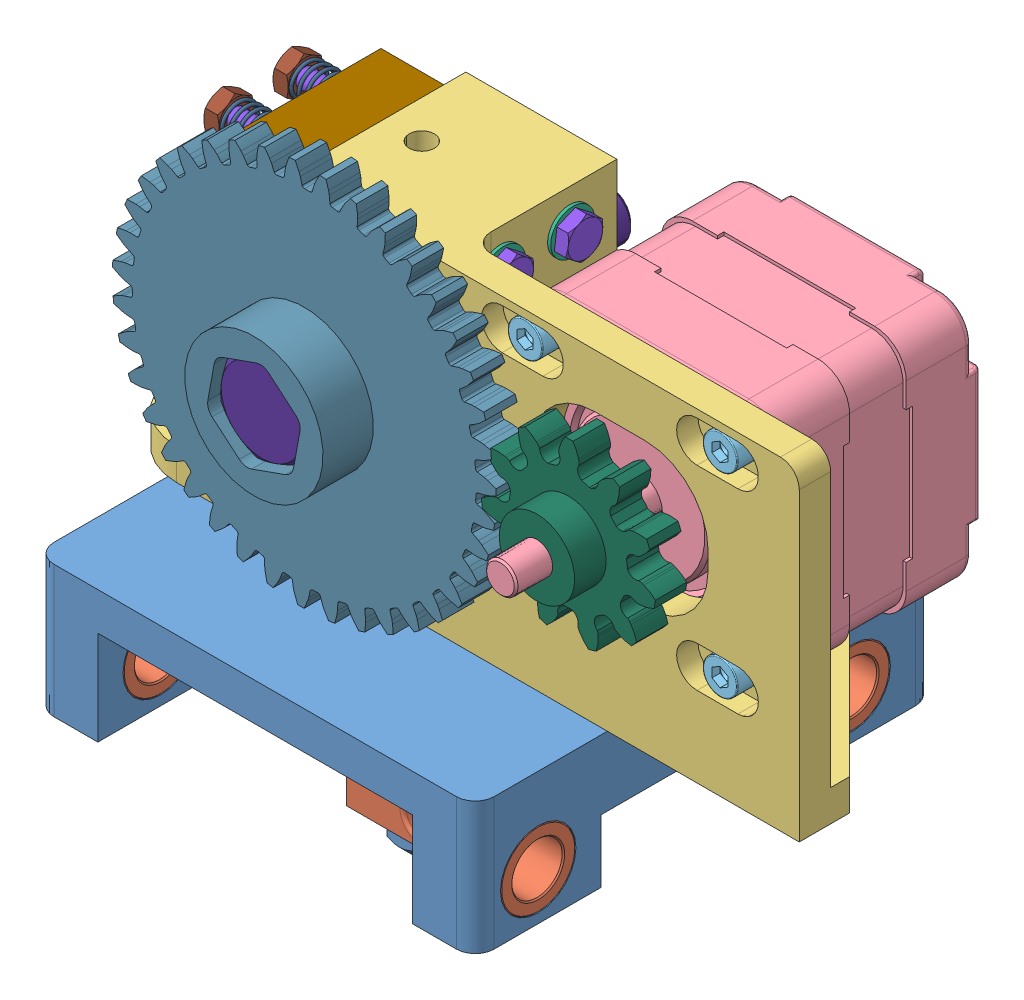
SolidWorks assembly X-Chariot, configuration Défaut. Lengths in mm.
Overall size (113.48 121.48 91.5).
86 component instances, 22 part files, 11 mates.
Components (placement in the parent):
- Chariot_Extrudeuse-1: Chariot_Extrudeuse [Défaut] at (18.2615 62.9748 98.4963) x (1 0 0) z (0 0 -1) size (70 21 91.5)
- BG 12x8x10-4: BG 12x8x10 [Défaut] at (78.2615 49.4748 88.4963) x (0 0.932939 0.360033) z (1 0 0) size (12 12 10)
- X-Tete_Extrusion-2: X-Tete_Extrusion [Défaut] at (67.2193 48.3843 48.66) size (113.48 192.54 59.4)
  - Extruder Body-1: Extruder Body [Défaut] at (51.5422 19.5906 0.8363) x (-1 0 0) z (0 0 -1) size (109 51.5 28)
  - plain washer grade a_din_Washer DIN 125 - A 3.7-1: plain washer grade a_din_Washer DIN 125 - A 3.7 [Défaut] at (-44.9578 19.5906 7.8363) x (0 -1 0) z (0 0 1) size (0.5 8 8) (hidden)
  - plain washer grade a_din_Washer DIN 125 - A 3.7-2: plain washer grade a_din_Washer DIN 125 - A 3.7 [Défaut] at (-44.9578 19.5906 21.8363) x (0 -1 0) z (0 0 1) size (0.5 8 8) (hidden)
  - plain washer grade a_din_Washer DIN 125 - A 3.7-3: plain washer grade a_din_Washer DIN 125 - A 3.7 [Défaut] at (16.0422 19.5906 6.5863) x (0 -1 0) z (0 0 1) size (0.5 8 8) (hidden)
  - plain washer grade a_din_Washer DIN 125 - A 3.7-4: plain washer grade a_din_Washer DIN 125 - A 3.7 [Défaut] at (16.0422 19.5906 18.0863) x (0 -1 0) z (0 0 1) size (0.5 8 8) (hidden)
  - plain washer grade a_din_Washer DIN 125 - A 3.7-5: plain washer grade a_din_Washer DIN 125 - A 3.7 [Défaut] at (16.0422 3.5906 6.5863) x (0 1 0) z (0 0 1) size (0.5 8 8) (hidden)
  - plain washer grade a_din_Washer DIN 125 - A 3.7-6: plain washer grade a_din_Washer DIN 125 - A 3.7 [Défaut] at (16.0422 3.5906 18.0863) x (0 1 0) z (0 0 1) size (0.5 8 8) (hidden)
  - plain washer grade a_din_Washer DIN 125 - A 3.7-7: plain washer grade a_din_Washer DIN 125 - A 3.7 [Défaut] at (-44.9578 3.5906 7.8363) x (0 1 0) z (0 0 1) size (0.5 8 8) (hidden)
  - plain washer grade a_din_Washer DIN 125 - A 3.7-8: plain washer grade a_din_Washer DIN 125 - A 3.7 [Défaut] at (-44.9578 3.5906 21.8363) x (0 1 0) z (0 0 1) size (0.5 8 8) (hidden)
  - hex bolt gradeb_iso_ISO 4015 - M3 x 20 x 20-C-1: hex bolt gradeb_iso_ISO 4015 - M3 x 20 x 20-C [Défaut] at (-44.9578 22.0906 21.8363) x (0 -1 0) z (0 0 1) size (22 6.35 5.5) (hidden)
  - hex bolt gradeb_iso_ISO 4015 - M3 x 20 x 20-C-2: hex bolt gradeb_iso_ISO 4015 - M3 x 20 x 20-C [Défaut] at (-44.9578 22.0906 7.8363) x (0 -1 0) z (0 0 1) size (22 6.35 5.5) (hidden)
  - hex bolt gradeb_iso_ISO 4015 - M3 x 20 x 20-C-3: hex bolt gradeb_iso_ISO 4015 - M3 x 20 x 20-C [Défaut] at (16.0422 22.0906 6.5863) x (0 -1 0) z (0 0 1) size (22 6.35 5.5) (hidden)
  - hex bolt gradeb_iso_ISO 4015 - M3 x 20 x 20-C-4: hex bolt gradeb_iso_ISO 4015 - M3 x 20 x 20-C [Défaut] at (16.0422 22.0906 18.0863) x (0 -1 0) z (0 0 1) size (22 6.35 5.5) (hidden)
  - hex nut style 1 gradeab_iso_Hexagon Nut ISO - 4032 - M3 - D - C-1: hex nut style 1 gradeab_iso_Hexagon Nut ISO - 4032 - M3 - D - C [Défaut] at (-44.9578 0.6906 21.8363) x (1 0 0) z (0 -1 0) size (5.5 6.35 2.4) (hidden)
  - hex nut style 1 gradeab_iso_Hexagon Nut ISO - 4032 - M3 - D - C-2: hex nut style 1 gradeab_iso_Hexagon Nut ISO - 4032 - M3 - D - C [Défaut] at (-44.9578 0.6906 7.8363) x (1 0 0) z (0 -1 0) size (5.5 6.35 2.4) (hidden)
  - hex nut style 1 gradeab_iso_Hexagon Nut ISO - 4032 - M3 - D - C-3: hex nut style 1 gradeab_iso_Hexagon Nut ISO - 4032 - M3 - D - C [Défaut] at (16.0422 0.6906 6.5863) x (1 0 0) z (0 -1 0) size (5.5 6.35 2.4) (hidden)
  - hex nut style 1 gradeab_iso_Hexagon Nut ISO - 4032 - M3 - D - C-4: hex nut style 1 gradeab_iso_Hexagon Nut ISO - 4032 - M3 - D - C [Défaut] at (16.0422 0.6906 18.0863) x (1 0 0) z (0 -1 0) size (5.5 6.35 2.4) (hidden)
  - NEMA 17 Bipolar Stepper Motor-1: NEMA 17 Bipolar Stepper Motor [Défaut] at (23.0422 46.0906 7.3363) x (0 0 1) z (-1 0 0) size (57.01 39.01 39.01)
  - socket head cap screw_iso_ISO 4762 M3 x 5 --- 5C-1: socket head cap screw_iso_ISO 4762 M3 x 5 --- 5C [Défaut] at (7.5422 61.5906 28.4363) x (0 0 -1) z (1 0 0) size (8 5.5 5.5)
  - socket head cap screw_iso_ISO 4762 M3 x 5 --- 5C-2: socket head cap screw_iso_ISO 4762 M3 x 5 --- 5C [Défaut] at (38.5422 61.5906 28.4363) x (0 0 -1) z (1 0 0) size (8 5.5 5.5)
  - socket head cap screw_iso_ISO 4762 M3 x 5 --- 5C-3: socket head cap screw_iso_ISO 4762 M3 x 5 --- 5C [Défaut] at (7.5422 30.5906 28.4363) x (0 0 -1) z (1 0 0) size (8 5.5 5.5)
  - socket head cap screw_iso_ISO 4762 M3 x 5 --- 5C-4: socket head cap screw_iso_ISO 4762 M3 x 5 --- 5C [Défaut] at (38.5422 30.5906 28.4363) x (0 0 -1) z (1 0 0) size (8 5.5 5.5)
  - plain washer grade a_din_Washer DIN 125 - A 3.2-1: plain washer grade a_din_Washer DIN 125 - A 3.2 [Défaut] at (-29.4578 60.0906 8.3363) size (0.5 7 7)
  - plain washer grade a_din_Washer DIN 125 - A 3.2-2: plain washer grade a_din_Washer DIN 125 - A 3.2 [Défaut] at (-29.9578 60.0906 8.3363) size (0.5 7 7)
  - plain washer grade a_din_Washer DIN 125 - A 3.2-3: plain washer grade a_din_Washer DIN 125 - A 3.2 [Défaut] at (-30.4578 60.0906 8.3363) size (0.5 7 7)
  - plain washer grade a_din_Washer DIN 125 - A 3.2-4: plain washer grade a_din_Washer DIN 125 - A 3.2 [Défaut] at (-30.9578 60.0906 8.3363) x (1 0 0) z (0 0.451194 0.892426) size (0.5 7 7)
  - Smooth Rod - f8x23-1: Smooth Rod - f8x23 [Défaut] at (-34.4578 46.0906 2.3363) x (1 0 0) z (0 -1 0) size (8 23 8)
  - plain washer grade a_din_Washer DIN 125 - A 3.2-5: plain washer grade a_din_Washer DIN 125 - A 3.2 [Défaut] at (-5.4578 60.0906 19.3363) x (-1 0 0) z (0 0.924225 0.381849) size (0.5 7 7)
  - plain washer grade a_din_Washer DIN 125 - A 3.2-6: plain washer grade a_din_Washer DIN 125 - A 3.2 [Défaut] at (-5.4578 60.0906 8.3363) x (-1 0 0) z (0 0.924225 0.381849) size (0.5 7 7)
  - plain washer grade a_din_Washer DIN 125 - A 3.2-7: plain washer grade a_din_Washer DIN 125 - A 3.2 [Défaut] at (-5.4578 32.0906 8.3363) x (-1 0 0) z (0 0.924225 0.381849) size (0.5 7 7)
  - plain washer grade a_din_Washer DIN 125 - A 3.2-8: plain washer grade a_din_Washer DIN 125 - A 3.2 [Défaut] at (-5.4578 32.0906 19.3363) x (-1 0 0) z (0 0.924225 0.381849) size (0.5 7 7)
  - plain washer grade a_din_Washer DIN 125 - A 3.2-9: plain washer grade a_din_Washer DIN 125 - A 3.2 [Défaut] at (-29.4578 60.0906 19.3363) size (0.5 7 7)
  - plain washer grade a_din_Washer DIN 125 - A 3.2-10: plain washer grade a_din_Washer DIN 125 - A 3.2 [Défaut] at (-29.4578 32.0906 19.3363) size (0.5 7 7)
  - plain washer grade a_din_Washer DIN 125 - A 3.2-11: plain washer grade a_din_Washer DIN 125 - A 3.2 [Défaut] at (-29.4578 32.0906 8.3363) size (0.5 7 7)
  - plain washer grade a_din_Washer DIN 125 - A 3.2-12: plain washer grade a_din_Washer DIN 125 - A 3.2 [Défaut] at (-29.9578 60.0906 19.3363) size (0.5 7 7)
  - plain washer grade a_din_Washer DIN 125 - A 3.2-13: plain washer grade a_din_Washer DIN 125 - A 3.2 [Défaut] at (-30.4578 60.0906 19.3363) size (0.5 7 7)
  - plain washer grade a_din_Washer DIN 125 - A 3.2-14: plain washer grade a_din_Washer DIN 125 - A 3.2 [Défaut] at (-29.9578 32.0906 19.3363) size (0.5 7 7)
  - plain washer grade a_din_Washer DIN 125 - A 3.2-15: plain washer grade a_din_Washer DIN 125 - A 3.2 [Défaut] at (-30.4578 32.0906 19.3363) size (0.5 7 7)
  - plain washer grade a_din_Washer DIN 125 - A 3.2-16: plain washer grade a_din_Washer DIN 125 - A 3.2 [Défaut] at (-30.9578 32.0906 19.3363) size (0.5 7 7)
  - plain washer grade a_din_Washer DIN 125 - A 3.2-17: plain washer grade a_din_Washer DIN 125 - A 3.2 [Défaut] at (-29.9578 32.0906 8.3363) size (0.5 7 7)
  - plain washer grade a_din_Washer DIN 125 - A 3.2-18: plain washer grade a_din_Washer DIN 125 - A 3.2 [Défaut] at (-30.4578 32.0906 8.3363) size (0.5 7 7)
  - plain washer grade a_din_Washer DIN 125 - A 3.2-19: plain washer grade a_din_Washer DIN 125 - A 3.2 [Défaut] at (-30.9578 32.0906 8.3363) size (0.5 7 7)
  - M3x45_ISO 4015 - M3 x 45 x 12-C-1: M3x45_ISO 4015 - M3 x 45 x 12-C [Défaut] at (-2.9578 60.0906 19.3363) x (-1 0 0) z (0 -0.924225 -0.381849) size (47 6.35 5.5)
  - M3x45_ISO 4015 - M3 x 45 x 12-C-2: M3x45_ISO 4015 - M3 x 45 x 12-C [Défaut] at (-2.9578 32.0906 8.3363) x (-1 0 0) z (0 -0.924225 -0.381849) size (47 6.35 5.5)
  - M3x45_ISO 4015 - M3 x 45 x 12-C-3: M3x45_ISO 4015 - M3 x 45 x 12-C [Défaut] at (-2.9578 32.0906 19.3363) x (-1 0 0) z (0 -0.924225 -0.381849) size (47 6.35 5.5)
  - M3x45_ISO 4015 - M3 x 45 x 12-C-4: M3x45_ISO 4015 - M3 x 45 x 12-C [Défaut] at (-2.9578 60.0906 8.3363) x (-1 0 0) z (0 -0.924225 -0.381849) size (47 6.35 5.5)
  - Idler Body-1: Idler Body [Défaut] at (-41.4578 28.0906 25.3363) x (0 0 -1) z (1 0 0) size (23 36 10)
  - plain washer grade a_din_Washer DIN 125 - A 3.2-20: plain washer grade a_din_Washer DIN 125 - A 3.2 [Défaut] at (-30.9578 60.0906 19.3363) size (0.5 7 7)
  - plain washer grade a_din_Washer DIN 125 - A 3.2-21: plain washer grade a_din_Washer DIN 125 - A 3.2 [Défaut] at (-41.4578 60.0906 8.3363) x (1 0 0) z (0 -0.022823 0.99974) size (0.5 7 7)
  - plain washer grade a_din_Washer DIN 125 - A 3.2-22: plain washer grade a_din_Washer DIN 125 - A 3.2 [Défaut] at (-41.4578 60.0906 19.3363) size (0.5 7 7)
  - plain washer grade a_din_Washer DIN 125 - A 3.2-23: plain washer grade a_din_Washer DIN 125 - A 3.2 [Défaut] at (-41.4578 32.0906 19.3363) size (0.5 7 7)
  - plain washer grade a_din_Washer DIN 125 - A 3.2-24: plain washer grade a_din_Washer DIN 125 - A 3.2 [Défaut] at (-41.4578 32.0906 8.3363) size (0.5 7 7)
  - Ballpoint Pen Spring - Extruder-1: Ballpoint Pen Spring - Extruder [Défaut] at (-42.2078 60.0906 8.3363) x (0 0.991476 -0.130286) z (0 0.130286 0.991476) size (5.53 5.52 5.5)
  - Ballpoint Pen Spring - Extruder-2: Ballpoint Pen Spring - Extruder [Défaut] at (-42.2078 60.0906 19.3363) x (0 0.999694 0.024727) z (0 -0.024727 0.999694) size (5.53 5.52 5.5)
  - Ballpoint Pen Spring - Extruder-3: Ballpoint Pen Spring - Extruder [Défaut] at (-42.2078 32.0906 8.3363) x (0 0.999047 -0.043643) z (0 0.043643 0.999047) size (5.53 5.52 5.5)
  - Ballpoint Pen Spring - Extruder-4: Ballpoint Pen Spring - Extruder [Défaut] at (-42.2078 32.0906 19.3363) x (0 0.978843 -0.20461) z (0 0.20461 0.978843) size (5.53 5.52 5.5)
  - hex nut style 1 gradeab_iso_Hexagon Nut ISO - 4032 - M3 - D - C-5: hex nut style 1 gradeab_iso_Hexagon Nut ISO - 4032 - M3 - D - C [Défaut] at (-47.4578 60.0906 8.3363) x (0 0 -1) z (1 0 0) size (5.5 6.35 2.4)
  - hex nut style 1 gradeab_iso_Hexagon Nut ISO - 4032 - M3 - D - C-6: hex nut style 1 gradeab_iso_Hexagon Nut ISO - 4032 - M3 - D - C [Défaut] at (-47.4578 60.0906 19.3363) x (0 0 -1) z (1 0 0) size (5.5 6.35 2.4)
  - hex nut style 1 gradeab_iso_Hexagon Nut ISO - 4032 - M3 - D - C-7: hex nut style 1 gradeab_iso_Hexagon Nut ISO - 4032 - M3 - D - C [Défaut] at (-46.9578 32.0906 8.3363) x (0 0.019138 -0.999817) z (1 0 0) size (5.5 6.35 2.4)
  - hex nut style 1 gradeab_iso_Hexagon Nut ISO - 4032 - M3 - D - C-8: hex nut style 1 gradeab_iso_Hexagon Nut ISO - 4032 - M3 - D - C [Défaut] at (-47.4578 32.0906 19.3363) x (0 0.048448 -0.998826) z (1 0 0) size (5.5 6.35 2.4)
  - Fourreau-1: Fourreau [Défaut] at (-23.4578 24.5906 13.8363) x (-1 0 0) z (0 0 -1) size (20 44 20)
  - plain washer grade a_din_Washer DIN 125 - A 8.4-1: plain washer grade a_din_Washer DIN 125 - A 8.4 [Défaut] at (-18.9578 46.0906 28.8363) x (0 0 -1) z (0.999888 -0.014961 0) size (1.6 16 16)
  - Large Gear-1: Large Gear [Défaut] at (-47.7391 12.1511 32.0363) x (-0.64677 -0.762685 0) z (0 0 1) size (60.98 60.94 13)
  - plain washer grade a_din_Washer DIN 125 - A 8.4-2: plain washer grade a_din_Washer DIN 125 - A 8.4 [Défaut] at (-18.9578 46.0906 -0.7637) x (0 0 -1) z (0.808623 0.588327 0) size (1.6 16 16)
  - Motor Shaft Pulley - Extruder-1: Motor Shaft Pulley - Extruder [Défaut] at (5.4114 54.4147 32.0363) x (0.336489 -0.941687 0) z (0 0 1) size (27.58 27.61 10)
  - plain washer grade a_din_Washer DIN 125 - A 3.2-25: plain washer grade a_din_Washer DIN 125 - A 3.2 [Défaut] at (-29.4578 19.5906 28.8363) x (0 0 -1) z (1 0 0) size (0.5 7 7)
  - plain washer grade a_din_Washer DIN 125 - A 3.2-26: plain washer grade a_din_Washer DIN 125 - A 3.2 [Défaut] at (-17.4578 19.5906 28.8363) x (0 0 -1) z (1 0 0) size (0.5 7 7)
  - plain washer grade a_din_Washer DIN 125 - A 3.2-27: plain washer grade a_din_Washer DIN 125 - A 3.2 [Défaut] at (-29.4578 19.5906 0.8363) x (0 0 1) z (-1 0 0) size (0.5 7 7)
  - plain washer grade a_din_Washer DIN 125 - A 3.2-28: plain washer grade a_din_Washer DIN 125 - A 3.2 [Défaut] at (-17.4578 19.5906 0.8363) x (0 0 1) z (-1 0 0) size (0.5 7 7)
  - hex bolt gradeb_iso_ISO 4015 - M3 x 20 x 12-C-1: hex bolt gradeb_iso_ISO 4015 - M3 x 20 x 12-C [Défaut] at (-17.4578 19.5906 31.3363) x (0 0 -1) z (1 0 0) size (22 6.35 5.5)
  - hex bolt gradeb_iso_ISO 4015 - M3 x 20 x 12-C-2: hex bolt gradeb_iso_ISO 4015 - M3 x 20 x 12-C [Défaut] at (-29.4578 19.5906 31.3363) x (0 0 -1) z (1 0 0) size (22 6.35 5.5)
  - hex bolt gradeb_iso_ISO 4015 - M3 x 20 x 12-C-3: hex bolt gradeb_iso_ISO 4015 - M3 x 20 x 12-C [Défaut] at (-17.4578 19.5906 -1.6637) x (0 0 1) z (-1 0 0) size (22 6.35 5.5)
  - hex bolt gradeb_iso_ISO 4015 - M3 x 20 x 12-C-4: hex bolt gradeb_iso_ISO 4015 - M3 x 20 x 12-C [Défaut] at (-29.4578 19.5906 -1.6637) x (0 0 1) z (-1 0 0) size (22 6.35 5.5)
  - plain washer grade a_din_Washer DIN 125 - A 8.4-3: plain washer grade a_din_Washer DIN 125 - A 8.4 [Défaut] at (-18.9578 46.0906 30.4363) x (0 0 -1) z (0.820893 -0.571083 0) size (1.6 16 16)
  - hex bolt gradeb_iso_ISO 4015 - M8 x 50 x 22-C-1: hex bolt gradeb_iso_ISO 4015 - M8 x 50 x 22-C [Défaut] at (-18.9578 46.0906 43.7363) x (0 0 -1) z (0.98389 -0.178776 0) size (55.3 15.01 13)
  - radial ball bearing_68_skf_SKF - 608 - Full,DE,AC,Full_68-1: radial ball bearing_68_skf_SKF - 608 - Full,DE,AC,Full_68 [Défaut] at (-18.9578 46.0906 25.3363) x (0 0 1) z (-1 0 0) size (7.01 22 22)
  - radial ball bearing_68_skf_SKF - 608 - Full,DE,AC,Full_68-2: radial ball bearing_68_skf_SKF - 608 - Full,DE,AC,Full_68 [Défaut] at (-18.9578 46.0906 4.3363) x (0 0 1) z (-1 0 0) size (7.01 22 22)
  - radial ball bearing_68_skf_SKF - 608 - Full,DE,AC,Full_68-3: radial ball bearing_68_skf_SKF - 608 - Full,DE,AC,Full_68 [Défaut] at (-34.4578 46.0906 13.8363) x (0 0 -1) z (1 0 0) size (7.01 22 22)
  - Buse-1: Buse [Défaut] at (-23.4578 -32.4094 13.8363) x (0 1 0) z (0 0 1) size (13 8.89 7)
  - Support résistance-1: Support résistance [Défaut] at (-27.4578 -23.4094 5.8363) size (16 8 16)
- BG 12x8x10-8: BG 12x8x10 [Défaut] at (78.2615 49.4748 38.4963) x (0 0.071343 -0.997452) z (1 0 0) size (12 12 10)
- BG 12x8x10-10: BG 12x8x10 [Défaut] at (18.2615 49.4748 88.4963) x (0 0.19777 -0.980248) z (1 0 0) size (12 12 10)
- BG 12x8x10-12: BG 12x8x10 [Défaut] at (18.2615 49.4748 38.4963) x (0 0.28828 -0.957546) z (1 0 0) size (12 12 10)
Mates (geometry in assembly coordinates):
- Coaxiale5: concentric aligned: cylinder of Chariot_Extrudeuse-1 through (88.2615 49.4748 88.4963) axis (-1 0 0) radius 6; cylinder of BG 12x8x10-4 through (88.2615 49.4748 88.4963) axis (-1 0 0) radius 6
- Coïncidente3: coincident aligned: plane of Chariot_Extrudeuse-1 through (88.2615 56.9748 98.4963) normal (1 0 0); plane of BG 12x8x10-4 through (88.2615 49.4748 88.4963) normal (1 0 0)
- Coïncidente4: coincident anti-aligned: plane of Chariot_Extrudeuse-1 through (70.7615 62.9748 14.4963) normal (0 1 0); plane of X-Tete_Extrusion-2/Extruder Body-1 through (118.7615 62.9748 77.4963) normal (0 -1 0)
- Coaxiale6: concentric anti-aligned: cylinder of Chariot_Extrudeuse-1 through (83.2615 51.9748 66.7463) axis (0 -1 0) radius 1.7; cylinder of X-Tete_Extrusion-2/Extruder Body-1 through (83.2615 67.9748 66.7463) axis (0 1 0) radius 1.7
- Parallèle2: parallel aligned: plane of Chariot_Extrudeuse-1 through (18.2615 56.9748 98.4963) normal (0 0 1); plane of X-Tete_Extrusion-2/Extruder Body-1 through (118.7615 114.4748 77.4963) normal (0 0 1)
- Coaxiale10: concentric aligned: cylinder of Chariot_Extrudeuse-1 through (88.2615 49.4748 38.4963) axis (-1 0 0) radius 6; cylinder of BG 12x8x10-8 through (88.2615 49.4748 38.4963) axis (-1 0 0) radius 6
- Coïncidente7: coincident aligned: plane of Chariot_Extrudeuse-1 through (88.2615 56.9748 98.4963) normal (1 0 0); plane of BG 12x8x10-8 through (88.2615 49.4748 38.4963) normal (1 0 0)
- Coaxiale11: concentric aligned: cylinder of Chariot_Extrudeuse-1 through (88.2615 49.4748 88.4963) axis (-1 0 0) radius 6; cylinder of BG 12x8x10-10 through (28.2615 49.4748 88.4963) axis (-1 0 0) radius 6
- Coïncidente8: coincident aligned: plane of Chariot_Extrudeuse-1 through (28.2615 41.9748 98.4963) normal (1 0 0); plane of BG 12x8x10-10 through (28.2615 49.4748 88.4963) normal (1 0 0)
- Coaxiale12: concentric aligned: cylinder of Chariot_Extrudeuse-1 through (88.2615 49.4748 38.4963) axis (-1 0 0) radius 6; cylinder of BG 12x8x10-12 through (28.2615 49.4748 38.4963) axis (-1 0 0) radius 6
- Coïncidente9: coincident aligned: plane of Chariot_Extrudeuse-1 through (28.2615 41.9748 98.4963) normal (1 0 0); plane of BG 12x8x10-12 through (28.2615 49.4748 38.4963) normal (1 0 0)
